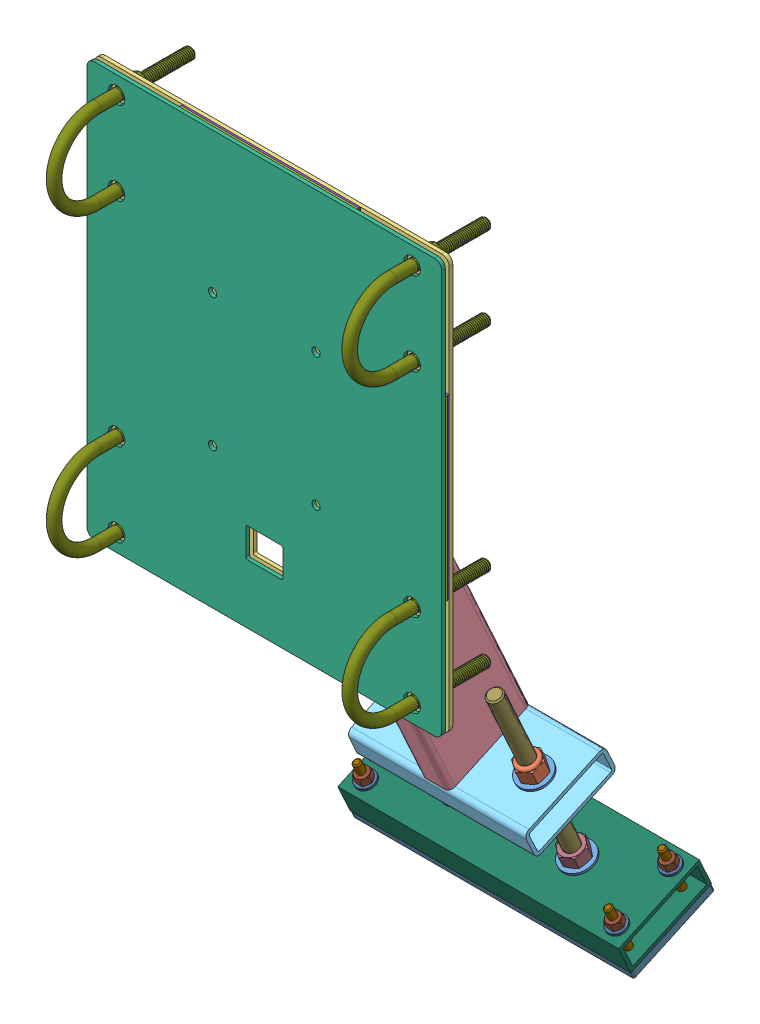
SolidWorks assembly GE-20067, configuration Default. Lengths in mm.
Overall size (304.8 1175.46 774.02).
57 component instances, 17 part files, 22 mates.
Components (placement in the parent):
- washer_flat_.5-2: washer_flat_.5 [98023A029] at (50.8 -368.9423 -183.4206) x (-0.977819 -0.086859 0.190594) z (-0.209453 0.405495 -0.889777) size (26.99 2.03 26.99)
- washer_flat_.5-3: washer_flat_.5 [98023A029] at (50.8 -342.1312 -171.202) x (-0.857421 0.213408 -0.46828) z (-0.514616 -0.355567 0.78022) size (26.99 2.03 26.99)
- nylock_.50_13-1: nylock_.50_13 [nylock_.5_13] at (50.8 -342.1312 -171.202) x (-0.997979 0.026348 -0.057816) z (0.063537 0.413855 -0.908123) size (19.05 15.73 22)
- nylock_.50_13-5: nylock_.50_13 [nylock_.5_13] at (50.8 -382.6657 -189.6746) x (-0.203443 -0.406021 0.890931) z (-0.979087 0.084366 -0.185125) size (19.05 15.73 22)
- GE-20088-1: GE-20088 [20090] at origin size (304.8 621.3 425.25)
  - GE-20081-1: GE-20081 [Default<As Machined>] at origin size (304.8 355.6 3.17)
  - GE-20082-1: GE-20082 [Default<As Machined>] at (0 -117.1838 -68.6876) x (0 -0.909961 -0.414693) z (-1 0 0) size (498.48 76.2 25.4)
  - GE-20086-1: GE-20086 [Default<As Machined>] at (0 -355.5368 -177.3113) x (1 0 0) z (0 -0.414693 0.909961) size (152.4 25.4 76.2)
- GE-20066-1: GE-20066 [Default] at (0 0 9.525) x (-1 0 0) z (0 0 -1) size (304.8 355.6 340.49)
  - GE-20087-1: GE-20087 [Default<As Machined>] at origin size (304.8 355.6 3.17)
  - Loop_1_6-2: Loop_1_6 [Default] at (-76.2 177.8 4.7625) x (1 0 0) z (0 1 0) size (152.4 1.59 25.4)
  - Loop_1_6-3: Loop_1_6 [Default] at (-152.4 -76.2 4.7625) x (0 1 0) z (-1 0 0) size (152.4 1.59 25.4)
  - Loop_1_6-4: Loop_1_6 [Default] at (152.4 76.2 4.7625) x (0 -1 0) z (1 0 0) size (152.4 1.59 25.4)
  - Loop_1_6-5: Loop_1_6 [Default] at (-76.2 -152.4 4.7625) x (1 0 0) z (0 1 0) size (152.4 1.59 25.4)
  - Hook_1_6-1: Hook_1_6 [Default] at (-152.4 -76.2 6.35) x (0 1 0) z (-1 0 0) size (152.4 1.59 25.4)
  - Hook_1_6-2: Hook_1_6 [Default] at (-76.2 177.8 6.35) x (1 0 0) z (0 1 0) size (152.4 1.59 25.4)
  - Hook_1_6-3: Hook_1_6 [Default] at (127 -76.2 6.35) x (0 1 0) z (-1 0 0) size (152.4 1.59 25.4)
  - Hook_1_6-4: Hook_1_6 [Default] at (-76.2 -152.4 6.35) x (1 0 0) z (0 1 0) size (152.4 1.59 25.4)
- GE-20072-1: GE-20072 [Default] at (0 -447.9888 -219.4441) x (1 0 0) z (0 -0.414693 0.909961) size (241.3 754.83 76.2)
  - flat_phil_.25_20_2-1: flat_phil_.25_20_2 [flat_phil_.25_20_2] at (-107.95 -2.0255 -25.4) x (0.990416 0 0.138116) z (0 -1 0) size (12.12 12.12 50.8)
  - washer_flat_.25-1: washer_flat_.25 [98023A029] at (-107.95 27.432 -25.4) x (1 0 0) z (0 0 -1) size (15.88 2.03 15.88)
  - nylock_.25_20-2: nylock_.25_20 [Default] at (-107.95 27.432 -25.4) x (0.027835 0 -0.999613) z (0.999613 0 0.027835) size (11.11 7.94 12.83)
  - washer_flat_.5-4: washer_flat_.5 [98023A029] at (-50.8 25.4 0) x (0.930219 0 -0.367005) z (0.367005 0 0.930219) size (26.99 2.03 26.99)
  - washer_flat_.5-5: washer_flat_.5 [98023A029] at (-50.8 20.32 0) x (0.99985 0 0.017307) z (-0.017307 0 0.99985) size (26.99 2.03 26.99)
  - hex_.5_13_7-3: hex_.5_13_7 [92865A732] at (-50.8 104.8544 0) x (0 1 0) z (-0.367005 0 0.930219) size (186.53 22 19.05)
  - hexnut_.5_13-3: hexnut_.5_13 [95462A033] at (-50.8 32.9882 0) x (0.989243 0 0.146284) z (0 -1 0) size (19.05 22 11.11)
  - GE-20085-1: GE-20085 [Default] x (1 0 0) z (0 -1 0) size (241.3 76.2 6.35)
  - GE-20084-2: GE-20084 [Default<As Machined>] at (0 12.7 0) size (241.3 25.4 76.2)
  - washer_flat_.25-2: washer_flat_.25 [98023A029] at (107.95 27.432 25.4) x (1 0 0) z (0 0 -1) size (15.88 2.03 15.88)
  - washer_flat_.25-3: washer_flat_.25 [98023A029] at (-107.95 27.432 25.4) x (1 0 0) z (0 0 -1) size (15.88 2.03 15.88)
  - washer_flat_.25-5: washer_flat_.25 [98023A029] at (107.95 27.432 -25.4) x (1 0 0) z (0 0 -1) size (15.88 2.03 15.88)
  - nylock_.25_20-3: nylock_.25_20 [Default] at (107.95 27.432 25.4) x (0.027835 0 -0.999613) z (0.999613 0 0.027835) size (11.11 7.94 12.83)
  - nylock_.25_20-4: nylock_.25_20 [Default] at (-107.95 27.432 25.4) x (0.027835 0 -0.999613) z (0.999613 0 0.027835) size (11.11 7.94 12.83)
  - nylock_.25_20-6: nylock_.25_20 [Default] at (107.95 27.432 -25.4) x (0.027835 0 -0.999613) z (0.999613 0 0.027835) size (11.11 7.94 12.83)
  - flat_phil_.25_20_2-2: flat_phil_.25_20_2 [flat_phil_.25_20_2] at (107.95 -2.0255 25.4) x (0.990416 0 0.138116) z (0 -1 0) size (12.12 12.12 50.8)
  - flat_phil_.25_20_2-3: flat_phil_.25_20_2 [flat_phil_.25_20_2] at (-107.95 -2.0255 25.4) x (0.990416 0 0.138116) z (0 -1 0) size (12.12 12.12 50.8)
  - flat_phil_.25_20_2-5: flat_phil_.25_20_2 [flat_phil_.25_20_2] at (107.95 -2.0255 -25.4) x (0.990416 0 0.138116) z (0 -1 0) size (12.12 12.12 50.8)
  - washer_flat_.5-6: washer_flat_.5 [98023A029] at (50.8 20.32 0) x (0.99985 0 0.017307) z (-0.017307 0 0.99985) size (26.99 2.03 26.99)
  - washer_flat_.5-9: washer_flat_.5 [98023A029] at (50.8 25.4 0) x (0.930219 0 -0.367005) z (0.367005 0 0.930219) size (26.99 2.03 26.99)
  - hexnut_.5_13-7: hexnut_.5_13 [95462A033] at (50.8 32.9882 0) x (0.989243 0 0.146284) z (0 -1 0) size (19.05 22 11.11)
  - hex_.5_13_7-4: hex_.5_13_7 [92865A732] at (50.8 104.8544 0) x (0 1 0) z (-0.367005 0 0.930219) size (186.53 22 19.05)
- nylock_.50_13-6: nylock_.50_13 [nylock_.5_13] at (-50.8 -382.6657 -189.6746) x (-0.203443 -0.406021 0.890931) z (-0.979087 0.084366 -0.185125) size (19.05 15.73 22)
- washer_flat_.5-4: washer_flat_.5 [98023A029] at (-50.8 -368.9423 -183.4206) x (-0.977819 -0.086859 0.190594) z (-0.209453 0.405495 -0.889777) size (26.99 2.03 26.99)
- washer_flat_.5-5: washer_flat_.5 [98023A029] at (-50.8 -342.1312 -171.202) x (-0.857421 0.213408 -0.46828) z (-0.514616 -0.355567 0.78022) size (26.99 2.03 26.99)
- nylock_.50_13-4: nylock_.50_13 [nylock_.5_13] at (-50.8 -342.1312 -171.202) x (-0.997979 0.026348 -0.057816) z (0.063537 0.413855 -0.908123) size (19.05 15.73 22)
- GE-20069-1: GE-20069 [8875T859] at (-127 127 27.4029) x (0 1 0) z (-1 0 0) size (87.94 123.06 14.29)
- GE-20069-2: GE-20069 [8875T859] at (127 127 27.4029) x (0 1 0) z (-1 0 0) size (87.94 123.06 14.29)
- GE-20069-3: GE-20069 [8875T859] at (-127 -127 27.4029) x (0 1 0) z (-1 0 0) size (87.94 123.06 14.29)
- GE-20069-4: GE-20069 [8875T859] at (127 -127 27.4029) x (0 1 0) z (-1 0 0) size (87.94 123.06 14.29)
- washer_flat_.375-2: washer_flat_.375 [98023A029] at (-127 162.7188 -2.032) x (1 0 0) z (0 -1 0) size (19.05 2.03 19.05)
- washer_flat_.375-3: washer_flat_.375 [98023A029] at (127 162.7188 -2.032) x (1 0 0) z (0 -1 0) size (19.05 2.03 19.05)
- washer_flat_.375-4: washer_flat_.375 [98023A029] at (127 91.2812 -2.032) x (1 0 0) z (0 -1 0) size (19.05 2.03 19.05)
- washer_flat_.375-5: washer_flat_.375 [98023A029] at (127 -91.2812 -2.032) x (1 0 0) z (0 -1 0) size (19.05 2.03 19.05)
- washer_flat_.375-6: washer_flat_.375 [98023A029] at (127 -162.7188 -2.032) x (1 0 0) z (0 -1 0) size (19.05 2.03 19.05)
- washer_flat_.375-7: washer_flat_.375 [98023A029] at (-127 -162.7188 -2.032) x (1 0 0) z (0 -1 0) size (19.05 2.03 19.05)
- washer_flat_.375-8: washer_flat_.375 [98023A029] at (-127 -91.2812 -2.032) x (1 0 0) z (0 -1 0) size (19.05 2.03 19.05)
- washer_flat_.375-9: washer_flat_.375 [98023A029] at (-127 91.2812 -2.032) x (1 0 0) z (0 -1 0) size (19.05 2.03 19.05)
Mates (geometry in assembly coordinates):
- Coincident1: coincident anti-aligned: plane of GE-20088-1/GE-20081-1 through (0 0 3.175) normal (0 0 1); plane of GE-20066-1/Hook_1_6-3 through (-127 -76.2 3.175) normal (0 0 -1)
- Coincident2: coincident aligned: plane of GE-20088-1/GE-20081-1 through (-152.4 177.8 3.175) normal (0 1 0); plane of GE-20066-1/GE-20087-1 through (152.4 177.8 6.35) normal (0 1 0)
- Coincident3: coincident aligned: plane of GE-20088-1/GE-20081-1 through (152.4 177.8 3.175) normal (1 0 0); plane of GE-20066-1/GE-20087-1 through (152.4 177.8 6.35) normal (1 0 0)
- Concentric1: concentric aligned: cylinder of GE-20088-1/GE-20086-1 through (50.8 -343.9803 -172.0447) axis (0 0.909961 0.414693) radius 6.7462; cylinder of GE-20072-1/hex_.5_13_7-4 through (50.8 -429.4984 -211.0176) axis (0 0.909961 0.414693) radius 6.35
- Concentric2: concentric aligned: cylinder of GE-20088-1/GE-20086-1 through (-50.8 -343.9803 -172.0447) axis (0 0.909961 0.414693) radius 6.7462; cylinder of GE-20072-1/hex_.5_13_7-3 through (-50.8 -429.4984 -211.0176) axis (0 0.909961 0.414693) radius 6.35
- Concentric31: concentric anti-aligned: cylinder of GE-20088-1/GE-20086-1 through (50.8 -343.9803 -172.0447) axis (0 0.909961 0.414693) radius 6.7462; cylinder of washer_flat_.5-2 through (50.8 -367.0933 -182.5779) axis (0 -0.909961 -0.414693) radius 13.4938
- Coincident41: coincident anti-aligned: plane of GE-20088-1/GE-20086-1 through (-76.2 -353.2684 -212.9137) normal (0 -0.909961 -0.414693); plane of washer_flat_.5-2 through (50.8 -367.0933 -182.5779) normal (0 0.909961 0.414693)
- Concentric41: concentric aligned: cylinder of GE-20088-1/GE-20086-1 through (50.8 -343.9803 -172.0447) axis (0 0.909961 0.414693) radius 6.7462; cylinder of washer_flat_.5-3 through (50.8 -343.9803 -172.0447) axis (0 0.909961 0.414693) radius 13.4938
- Coincident51: coincident anti-aligned: plane of GE-20088-1/GE-20086-1 through (-76.2 -357.8051 -141.7089) normal (0 0.909961 0.414693); plane of washer_flat_.5-3 through (50.8 -343.9803 -172.0447) normal (0 -0.909961 -0.414693)
- Concentric5: concentric anti-aligned: circle of washer_flat_.5-2; circle of nylock_.50_13-5
- Concentric6: concentric aligned: circle of washer_flat_.5-3; circle of nylock_.50_13-1
- Coincident6: coincident anti-aligned: plane of washer_flat_.5-3 through (50.8 -342.1312 -171.202) normal (0 0.909961 0.414693); plane of nylock_.50_13-1 through (50.1012 -346.683 -161.214) normal (0 -0.909961 -0.414693)
- Concentric7: concentric aligned: cylinder of GE-20066-1/GE-20087-1 through (-127 162.7188 6.35) axis (0 0 -1) radius 7.1437; cylinder of GE-20069-1 through (-127 162.7188 27.4029) axis (0 0 -1) radius 4.7625
- Concentric8: concentric aligned: cylinder of GE-20066-1/GE-20087-1 through (-127 91.2812 6.35) axis (0 0 -1) radius 7.1437; cylinder of GE-20069-1 through (-127 91.2812 9.1466) axis (0 0 -1) radius 4.7625
- Distance3: distance = 63.5 mm anti-aligned: plane of GE-20072-1/GE-20084-2 through (-120.65 -409.076 -243.5804) normal (0 0.909961 0.414693); plane of GE-20088-1/GE-20086-1 through (-76.2 -353.2684 -212.9137) normal (0 -0.909961 -0.414693)
- Concentric421: concentric aligned: cylinder of GE-20088-1/GE-20081-1 through (-127 162.7188 3.175) axis (0 0 1) radius 6.7469; cylinder of washer_flat_.375-2 through (-127 162.7188 -2.032) axis (0 0 1) radius 5.1562
- Coincident521: coincident anti-aligned: plane of GE-20088-1/GE-20081-1 through (0 0 0) normal (0 0 -1); plane of washer_flat_.375-2 through (-127 162.7188 0) normal (0 0 1)
- Coincident53: coincident anti-aligned: plane of GE-20069-1 through (-134.1438 166.8432 -2.032) normal (0 0 1); plane of washer_flat_.375-2 through (-127 162.7188 -2.032) normal (0 0 -1)
- Coincident522: coincident anti-aligned: plane of GE-20066-1/GE-20087-1 through (0 0 0) normal (0 0 -1)
- Coincident523: coincident aligned: plane of GE-20088-1 through (0 0 9.525) normal (0 1 0)
- Coincident524: coincident anti-aligned: plane of GE-20088-1 through (0 0 9.525) normal (-1 0 0)
- Coincident525: coincident aligned: plane of washer_flat_.5-2 through (50.8 -368.9423 -183.4206) normal (0 -0.909961 -0.414693); circle of nylock_.50_13-5
